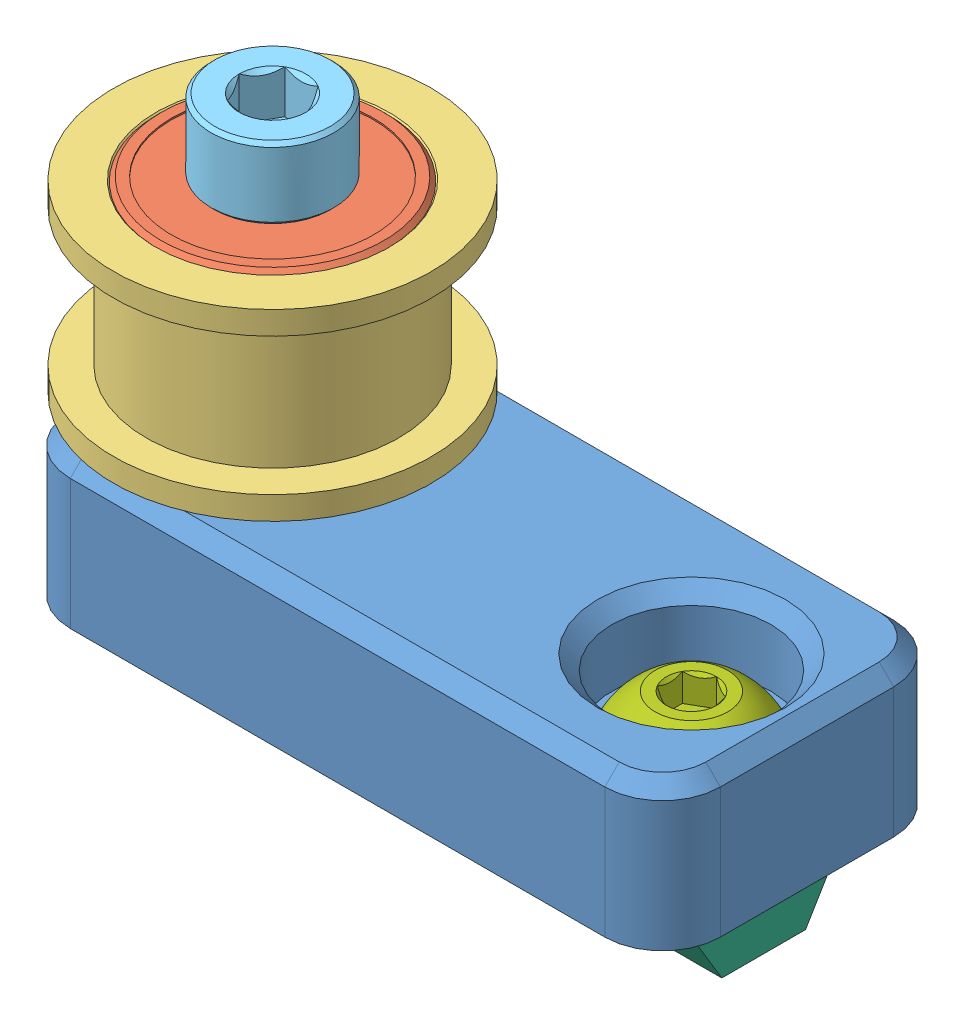
SolidWorks assembly Z_Belt_Idler, configuration Default. Lengths in mm.
Overall size (48.32 35.49 22.65).
9 component instances, 7 part files, 18 mates.
Components (placement in the parent):
- Z_Idler_Slide_Support-1: Z_Idler_Slide_Support [Default] at origin size (45 11.5 20)
- Ball_Bearing_625_2RS-1: Ball_Bearing_625_2RS [Défaut] at (-14.5 16.6 0) x (0 0 -1) z (1 0 0) size (16 5 16)
- Ball_Bearing_625_2RS-2: Ball_Bearing_625_2RS [Défaut] at (-14.5 8.5 0) x (-0.007951 0 -0.999968) z (0.999968 0 -0.007951) size (16 5 16)
- Smooth_Idler_Pulley-1: Smooth_Idler_Pulley [Default] at (-14.5 12.55 0) x (0.02991 0 -0.999553) z (0.999553 0 0.02991) size (22 12.7 22)
- Precision_Shim_10x5x1mm-1: Precision_Shim_10x5x1mm [Default] at (-14.5 5.5 0) x (0 0 -1) z (1 0 0) size (10 1 10)
- 5mmX30mm_Sockethead(McMaster_91290A254)-1: 5mmX30mm_Sockethead(McMaster_91290A254) [91290A254] at (-14.5 -10.9 0) x (0 0 -1) z (0 -1 0) size (8.5 8.5 35.49)
- HNTTSN5-5-1: HNTTSN5-5 [Default] at (-14.5 -6.2 0) x (0 1 0) z (1 0 0) size (4.3 10 10)
- 5mmX10mm_Buttonhead(McMaster_91239A224)-1: 5mmX10mm_Buttonhead(McMaster_91239A224) [91239A224] at (14.5 2.75 0) x (1 0 0) z (0 1 0) size (9.5 9.5 13.21)
- HNTTSN5-5-2: HNTTSN5-5 [Default] at (14.5 -6.2 0) x (0 1 0) z (-1 0 0) size (4.3 10 10)
Mates (geometry in assembly coordinates):
- Concentric1: concentric aligned: cylinder of Z_Idler_Slide_Support-1 through (14.5 -13.8539 0) axis (0 1 0) radius 2.6; cylinder of 5mmX10mm_Buttonhead(McMaster_91239A224)-1 through (14.5 2.75 0) axis (0 1 0) radius 4.75
- Coincident1: coincident anti-aligned: plane of Z_Idler_Slide_Support-1 through (14.5 0 0) normal (0 1 0); plane of 5mmX10mm_Buttonhead(McMaster_91239A224)-1 through (14.5 0 4.75) normal (0 -1 0)
- Concentric2: concentric anti-aligned: cylinder of Z_Idler_Slide_Support-1 through (14.5 -13.8539 0) axis (0 1 0) radius 2.6; cylinder of HNTTSN5-5-2 through (14.5 -6.2 0) axis (0 -1 0) radius 2.067
- Parallel1: parallel anti-aligned: plane of Z_Idler_Slide_Support-1 through (22.5 0 0) normal (1 0 0); plane of HNTTSN5-5-2 through (9.5 -6.2 0) normal (-1 0 0)
- Distance1: distance = 2 mm anti-aligned: plane of Z_Idler_Slide_Support-1 through (22.5 -5 10) normal (0 -1 0); plane of HNTTSN5-5-2 through (9.5 -7 -2.9) normal (0 1 0)
- Concentric3: concentric anti-aligned: cylinder of Ball_Bearing_625_2RS-1 through (-14.5 16.6 0) axis (0 -1 0) radius 8; cylinder of Smooth_Idler_Pulley-1 through (-14.5 43.0481 0) axis (0 1 0) radius 7.9875
- Concentric4: concentric anti-aligned: cylinder of Ball_Bearing_625_2RS-2 through (-14.5 8.5 0) axis (0 -1 0) radius 8; cylinder of Smooth_Idler_Pulley-1 through (-14.5 43.0481 0) axis (0 1 0) radius 7.9875
- Coincident4: coincident anti-aligned: plane of Ball_Bearing_625_2RS-1 through (-14.5 14.1 -7) normal (0 -1 0); plane of Smooth_Idler_Pulley-1 through (-14.2923 14.1 -6.9419) normal (0 1 0)
- Coincident5: coincident anti-aligned: plane of Ball_Bearing_625_2RS-2 through (-14.5557 11 -6.9998) normal (0 1 0); plane of Smooth_Idler_Pulley-1 through (-14.2923 11 -6.9419) normal (0 -1 0)
- Coincident6: coincident anti-aligned: plane of Ball_Bearing_625_2RS-2 through (-14.5223 6 -2.7999) normal (0 -1 0); plane of Precision_Shim_10x5x1mm-1 through (-14.5 6 0) normal (0 1 0)
- Concentric5: concentric aligned: cylinder of Ball_Bearing_625_2RS-2 through (-14.5 8.5 0) axis (0 -1 0) radius 2.5; cylinder of Precision_Shim_10x5x1mm-1 through (-14.5 6 0) axis (0 -1 0) radius 2.5
- Concentric6: concentric aligned: cylinder of Ball_Bearing_625_2RS-1 through (-14.5 16.6 0) axis (0 -1 0) radius 2.5; cylinder of 5mmX30mm_Sockethead(McMaster_91290A254)-1 through (-14.5 19.1 0) axis (0 -1 0) radius 2.5
- Coincident7: coincident anti-aligned: plane of Ball_Bearing_625_2RS-1 through (-14.5 19.1 -2.8) normal (0 1 0); plane of 5mmX30mm_Sockethead(McMaster_91290A254)-1 through (-14.5 19.1 0) normal (0 -1 0)
- Concentric7: concentric aligned: cylinder of 5mmX30mm_Sockethead(McMaster_91290A254)-1 through (-14.5 19.1 0) axis (0 -1 0) radius 2.5; cylinder of HNTTSN5-5-1 through (-14.5 -6.2 0) axis (0 -1 0) radius 2.067
- Parallel2: parallel anti-aligned: plane of Z_Idler_Slide_Support-1 through (-22.5 0 0) normal (-1 0 0); plane of HNTTSN5-5-1 through (-9.5 -6.2 0) normal (1 0 0)
- Concentric8: concentric anti-aligned: cylinder of Z_Idler_Slide_Support-1 through (-14.5 -13.8539 0) axis (0 1 0) radius 2.6; cylinder of 5mmX30mm_Sockethead(McMaster_91290A254)-1 through (-14.5 24.1 0) axis (0 -1 0) radius 4.25
- Coincident9: coincident anti-aligned: plane of Z_Idler_Slide_Support-1 through (22.5 5 10) normal (0 1 0); plane of Precision_Shim_10x5x1mm-1 through (-14.5 5 0) normal (0 -1 0)
- Coincident10: coincident aligned: plane of HNTTSN5-5-1 through (-9.5 -10.5 2.9) normal (0 -1 0); plane of HNTTSN5-5-2 through (9.5 -10.5 -2.9) normal (0 -1 0)
